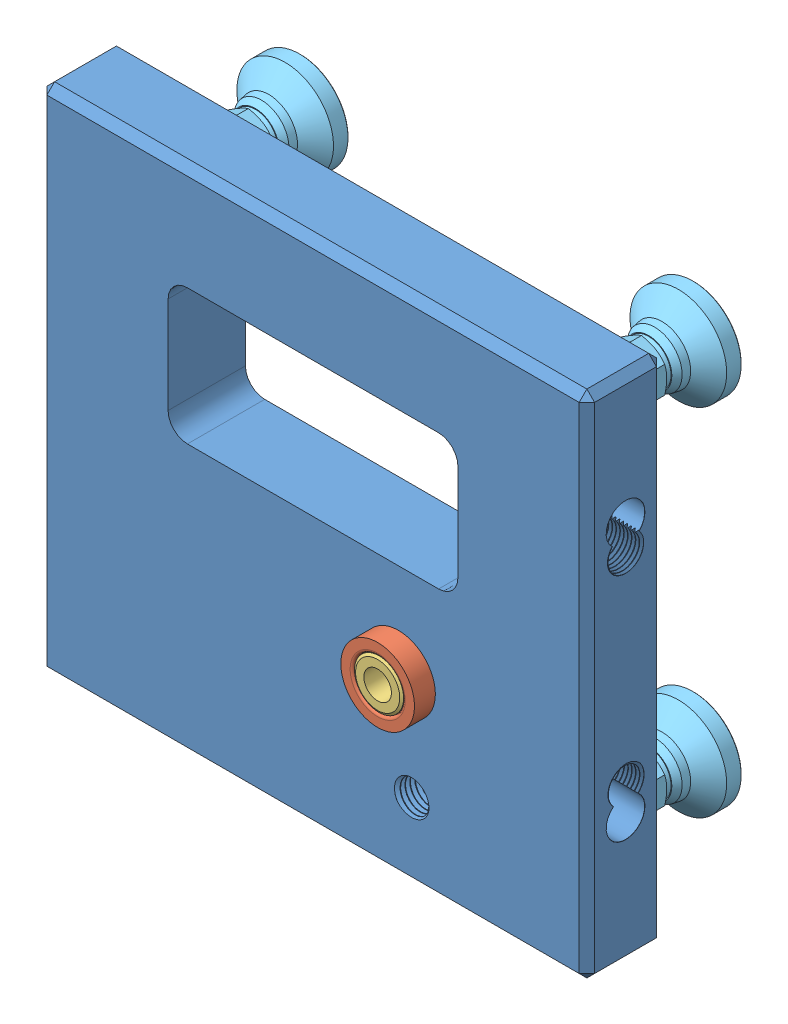
SolidWorks assembly Right Assembly, configuration Default. Lengths in mm.
Overall size (142.64 132 53.07).
9 component instances, 5 part files, 6 mates.
Components (placement in the parent):
- Right-1: Right [Default] at (74.2377 80.1668 93.3436)
- 7 mm Bushing-1: 7 mm Bushing [Default] at (85.3963 85.6757 106.083) x (0 0 1) z (0.868859 -0.495059 0) size (31.75 37.33 35.17)
  - 3556N159_Sleeve for Removable Drill Bushing-1: 3556N159_Sleeve for Removable Drill Bushing [3556N159] at (-0.0394 16.7346 22.1566)
  - 8493A169_Removable Drill Bushing-1: 8493A169_Removable Drill Bushing [8493A169] at (-3.2144 16.7346 22.1566) x (1 0 0) z (0 0.635804 0.771851)
  - 8496A13_Lock Screw for Removable Drill Bushings-1: 8496A13_Lock Screw for Removable Drill Bushings [8496A13] at (-7.6467 28.9877 12.0632) x (1 0 0) z (0 -0.868859 -0.495059)
- 6111K652_Swivel Leveling Mount-1: 6111K652_Swivel Leveling Mount [6111K652] at (23.3627 34.1668 90.1769) x (1 0 0) z (0 -1 0)
- 6111K652_Swivel Leveling Mount-5: 6111K652_Swivel Leveling Mount [6111K652] at (23.3627 126.1668 90.1769) x (1 0 0) z (0 -1 0)
- 6111K652_Swivel Leveling Mount-6: 6111K652_Swivel Leveling Mount [6111K652] at (125.1127 126.1668 90.1769) x (1 0 0) z (0 -1 0)
- 6111K652_Swivel Leveling Mount-7: 6111K652_Swivel Leveling Mount [6111K652] at (125.1127 34.1668 90.1769) x (1 0 0) z (0 -1 0)
Mates (geometry in assembly coordinates):
- Concentric2: concentric aligned: cylinder of Right-1 through (96.3627 60.1668 113.3436) axis (0 0 -1) radius 9.525; cylinder of 7 mm Bushing-1/3556N159_Sleeve for Removable Drill Bushing-1 through (96.3627 60.1668 93.3436) axis (0 0 -1) radius 9.525
- Coincident3: coincident anti-aligned: plane of Right-1 through (74.2377 80.1668 93.3436) normal (0 0 -1); plane of 7 mm Bushing-1/8493A169_Removable Drill Bushing-1 through (86.9049 56.5653 93.3436) normal (0 0 1)
- Parallel2: parallel aligned: plane of Right-1 through (145.1127 146.1668 113.3436) normal (1 0 0); plane of 7 mm Bushing-1/8496A13_Lock Screw for Removable Drill Bushings-1 through (80.3891 46.5799 92.0581) normal (1 0 0)
- Coincident5: coincident anti-aligned: plane of Right-1 through (74.2377 80.1668 93.3436) normal (0 0 -1); plane of 6111K652_Swivel Leveling Mount-1 through (23.3627 27.2386 93.3436) normal (0 0 1)
- Distance1: distance = 20 mm: cylinder of 6111K652_Swivel Leveling Mount-1 through (23.3627 34.1668 65.6769) axis (0 0 -1) radius 12.5; plane of Right-1 through (3.3627 14.1668 113.3436) normal (0 -1 0)
- Distance2: distance = 20 mm: cylinder of 6111K652_Swivel Leveling Mount-1 through (23.3627 34.1668 65.6769) axis (0 0 -1) radius 12.5; plane of Right-1 through (3.3627 146.1668 113.3436) normal (-1 0 0)
